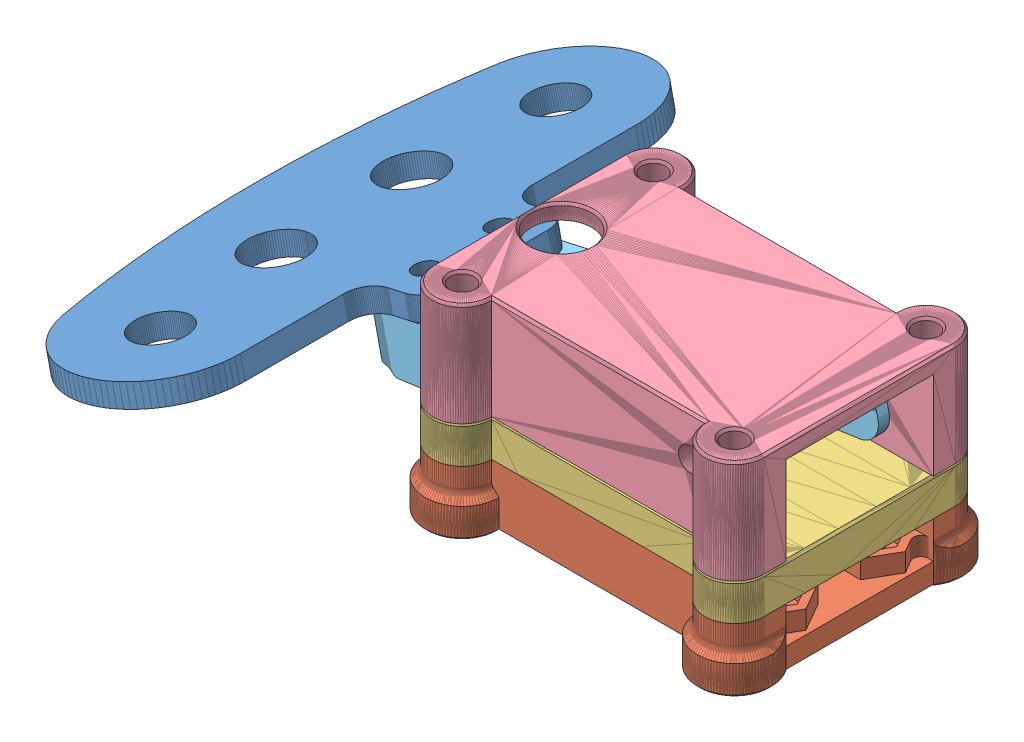
SolidWorks assembly mangentic pedal shifters assy, configuration Default. Lengths in mm.
Overall size (83.11 27 75.95).
5 component instances, 5 part files, 12 mates.
Components (placement in the parent):
- f1_paddle-1: f1_paddle [Default] at (-2.6636 15.9027 55.725) x (-0.975758 -0.218853 0) z (0 0 -1) size (33.6 3 75.95)
- shifter_unit_btm-1: shifter_unit_btm [Default] at origin size (47 8 36)
- shifter_unit_switch_stop_plate-1: shifter_unit_switch_stop_plate [Default] at (-7 8 35) x (1 0 0) z (0 1 0) size (53 34 5)
- shifter_unit_top-1: shifter_unit_top [Default] at (0.9034 13 35) x (1 0 0) z (0 1 0) size (45 34 14)
- paddle_hinge_v2-2: paddle_hinge_v2 [Default] at (-10.1177 3.2187 27.5) x (0.975758 0.218853 0) z (-0.218853 0.975758 0) size (52 19.5 10.74)
Mates (geometry in assembly coordinates):
- Coincident1: coincident anti-aligned: plane of f1_paddle-1 through (-2.6636 15.9027 55.725) normal (0.218853 -0.975758 0); plane of paddle_hinge_v2-2 through (-12.4693 13.7034 27.5) normal (-0.218853 0.975758 0)
- Coincident2: coincident aligned: plane of f1_paddle-1 through (-7.9419 14.7188 27.5) normal (0 0 1); plane of paddle_hinge_v2-2 through (-10.1177 3.2187 27.5) normal (0 0 1)
- Coincident4: coincident: point of f1_paddle-1; line of paddle_hinge_v2-2 through (-5.9814 15.1586 22.8024) axis (0 0 -1)
- Coincident5: coincident anti-aligned: plane of shifter_unit_top-1 through (0.9034 13 8) normal (0 0 1); plane of paddle_hinge_v2-2 through (-10.1177 3.2187 8) normal (0 0 -1)
- Coincident6: coincident aligned: line of shifter_unit_top-1 through (35.9993 21.4999 5) axis (0 0 -1); line of paddle_hinge_v2-2 through (35.9993 21.4999 8) axis (0 0 -1)
- Coincident7: coincident aligned: plane of shifter_unit_switch_stop_plate-1 through (-7 8 31) normal (0 0 1); plane of shifter_unit_top-1 through (0.9034 13 31) normal (0 0 1)
- Coincident8: coincident anti-aligned: plane of shifter_unit_switch_stop_plate-1 through (-7 13 35) normal (0 1 0); plane of shifter_unit_top-1 through (0.9034 13 35) normal (0 -1 0)
- Coincident9: coincident aligned: plane of shifter_unit_switch_stop_plate-1 through (46 8 35) normal (1 0 0); plane of shifter_unit_top-1 through (46 13 35) normal (1 0 0)
- Coincident10: coincident anti-aligned: plane of shifter_unit_btm-1 through (0 8 0) normal (0 1 0); plane of shifter_unit_switch_stop_plate-1 through (-7 8 35) normal (0 -1 0)
- Coincident11: coincident aligned: plane of shifter_unit_btm-1 through (0 0 31) normal (0 0 1); plane of shifter_unit_switch_stop_plate-1 through (-7 8 31) normal (0 0 1)
- Coincident12: coincident aligned: plane of shifter_unit_btm-1 through (46 0 0) normal (1 0 0); plane of shifter_unit_switch_stop_plate-1 through (46 8 35) normal (1 0 0)
- Coincident14: coordinate: unknown of shifter_unit_btm-1
